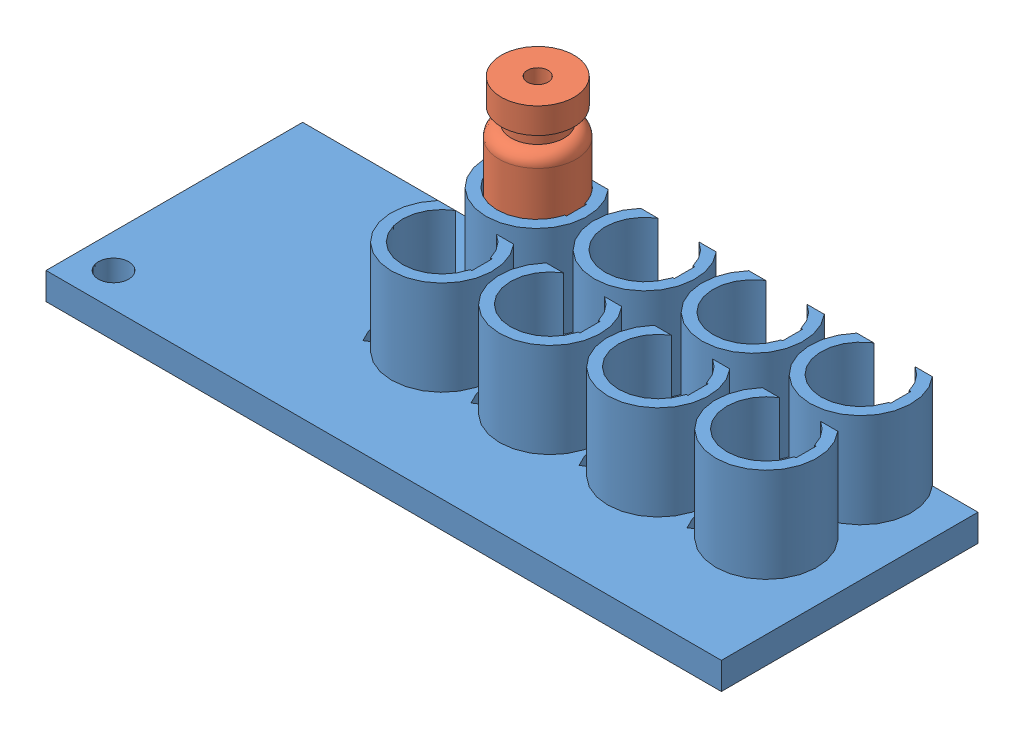
SolidWorks assembly Assem1, configuration Default. Lengths in mm.
Overall size (100 32.31 41.05).
2 component instances, 2 part files, 2 mates.
Components (placement in the parent):
- vialrack-1: vialrack [Default] at (-71.1083 -22.0887 1.0308) size (100 18 38)
- plasticvial-1: plasticvial [Default] at (-31.3024 -21.9761 6.0308) x (0.733936 0 -0.679218) z (0.679218 0 0.733936) size (11.4 32.2 11.4)
Mates (geometry in assembly coordinates):
- Coincident1: coincident: line of vialrack-1 through (-25.8033 -22.0887 4.5308) axis (0 1 0); cylinder of plasticvial-1 through (-31.3024 10.2239 6.0308) axis (0 1 0) radius 5.7
- Coincident2: coincident: line of vialrack-1 through (-25.8033 -22.0887 7.5308) axis (0 1 0); cylinder of plasticvial-1 through (-31.3024 10.2239 6.0308) axis (0 1 0) radius 5.7
